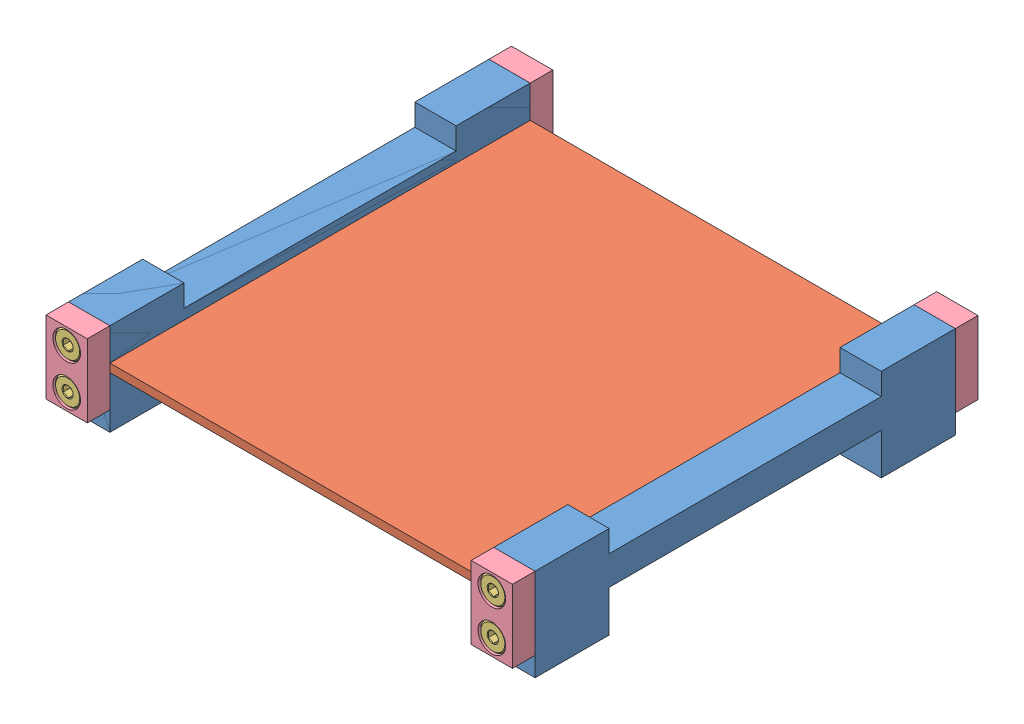
SolidWorks assembly Modified_Stack_Shelves_Assembly, configuration Default. Lengths in mm.
Overall size (96 19 95.8).
16 component instances, 4 part files, 18 mates.
Components (placement in the parent):
- Modified_PCB_Shelf-1: Modified_PCB_Shelf [Default] at origin size (8.5 19 86.5)
- FAKE_PCB-1: FAKE_PCB [Default] at (2.5 6.65 0) size (91 1.7 86.5)
- Modified_PCB_Shelf-2: Modified_PCB_Shelf [Default] at origin size (8.5 19 86.5)
- Modified_PCB_Shelf-4: Modified_PCB_Shelf [Default] at (96 0 -86.5) x (-1 0 0) z (0 0 -1) size (8.5 19 86.5)
- M3_LP_6MM_90666A103_TYPE 316 SS LOW PROFILE SOCKET HEAD CAP SCREW-3: M3_LP_6MM_90666A103_TYPE 316 SS LOW PROFILE SOCKET HEAD CAP SCREW [90666A103] at (4.25 11.675 -3.55) x (1 0 0) z (0 0 -1) size (5.5 5.5 8.16)
- M3_LP_6MM_90666A103_TYPE 316 SS LOW PROFILE SOCKET HEAD CAP SCREW-4: M3_LP_6MM_90666A103_TYPE 316 SS LOW PROFILE SOCKET HEAD CAP SCREW [90666A103] at (4.25 3.325 -3.55) x (1 0 0) z (0 0 -1) size (5.5 5.5 8.16)
- Modified_PCB_Shelf_End-7: Modified_PCB_Shelf_End [Default] at (4.25 7.5 0) size (8.5 15 4.65)
- Modified_PCB_Shelf_End-9: Modified_PCB_Shelf_End [Default] at (91.75 7.5 0) size (8.5 15 4.65)
- M3_LP_6MM_90666A103_TYPE 316 SS LOW PROFILE SOCKET HEAD CAP SCREW-9: M3_LP_6MM_90666A103_TYPE 316 SS LOW PROFILE SOCKET HEAD CAP SCREW [90666A103] at (91.75 11.675 -3.55) x (-1 0 0) z (0 0 -1) size (5.5 5.5 8.16)
- M3_LP_6MM_90666A103_TYPE 316 SS LOW PROFILE SOCKET HEAD CAP SCREW-10: M3_LP_6MM_90666A103_TYPE 316 SS LOW PROFILE SOCKET HEAD CAP SCREW [90666A103] at (91.75 3.325 -3.55) x (-1 0 0) z (0 0 -1) size (5.5 5.5 8.16)
- Modified_PCB_Shelf_End-12: Modified_PCB_Shelf_End [Default] at (91.75 7.5 -86.5) x (-1 0 0) z (0 0 -1) size (8.5 15 4.65)
- Modified_PCB_Shelf_End-13: Modified_PCB_Shelf_End [Default] at (4.25 7.5 -86.5) x (-1 0 0) z (0 0 -1) size (8.5 15 4.65)
- M3_LP_6MM_90666A103_TYPE 316 SS LOW PROFILE SOCKET HEAD CAP SCREW-15: M3_LP_6MM_90666A103_TYPE 316 SS LOW PROFILE SOCKET HEAD CAP SCREW [90666A103] at (4.25 11.675 -82.95) size (5.5 5.5 8.16)
- M3_LP_6MM_90666A103_TYPE 316 SS LOW PROFILE SOCKET HEAD CAP SCREW-16: M3_LP_6MM_90666A103_TYPE 316 SS LOW PROFILE SOCKET HEAD CAP SCREW [90666A103] at (4.25 3.325 -82.95) size (5.5 5.5 8.16)
- M3_LP_6MM_90666A103_TYPE 316 SS LOW PROFILE SOCKET HEAD CAP SCREW-17: M3_LP_6MM_90666A103_TYPE 316 SS LOW PROFILE SOCKET HEAD CAP SCREW [90666A103] at (91.75 11.675 -82.95) x (-1 0 0) z (0 0 1) size (5.5 5.5 8.16)
- M3_LP_6MM_90666A103_TYPE 316 SS LOW PROFILE SOCKET HEAD CAP SCREW-18: M3_LP_6MM_90666A103_TYPE 316 SS LOW PROFILE SOCKET HEAD CAP SCREW [90666A103] at (91.75 3.325 -82.95) x (-1 0 0) z (0 0 1) size (5.5 5.5 8.16)
Mates (geometry in assembly coordinates):
- Coincident1: coincident aligned: line of Modified_PCB_Shelf-1 through (2.5 8.35 -86.5) axis (0 0 1); line of FAKE_PCB-1 through (2.5 8.35 -86.5) axis (0 0 1)
- Coincident2: coincident anti-aligned: line of Modified_PCB_Shelf-1 through (1.7 2.5 6.65) axis (0 0 1); line of FAKE_PCB-1 through (1.7 2.5 8.35) axis (0 0 -1)
- Coincident5: coincident aligned: line of FAKE_PCB-1 through (93.5 8.35 0) axis (0 0 -1); line of Modified_PCB_Shelf-4 through (93.5 8.35 0) axis (0 0 -1)
- Coincident6: coincident anti-aligned: line of FAKE_PCB-1 through (1.7 93.5 8.35) axis (0 0 -1); line of Modified_PCB_Shelf-4 through (93.5 6.65 0) axis (0 1 0)
- Coincident15: coincident anti-aligned: plane of Modified_PCB_Shelf-1 through (8.5 15 0) normal (0 0 1); plane of Modified_PCB_Shelf_End-7 through (4.25 7.5 0) normal (0 0 -1)
- Coincident16: coincident aligned: line of Modified_PCB_Shelf-2 through (8.5 8.5 15) axis (0 -1 0); line of Modified_PCB_Shelf_End-7 through (8.5 8.5 15) axis (0 -1 0)
- Coincident17: coincident aligned: line of Modified_PCB_Shelf-1 through (0 15 0) axis (0 -1 0); line of Modified_PCB_Shelf_End-7 through (15 0 15) axis (0 0 -1)
- Coincident18: coincident anti-aligned: plane of M3_LP_6MM_90666A103_TYPE 316 SS LOW PROFILE SOCKET HEAD CAP SCREW-3 through (4.25 11.675 2.45) normal (0 0 -1); plane of Modified_PCB_Shelf_End-7 through (4.25 11.675 2.45) normal (0 0 1)
- Concentric3: concentric anti-aligned: circle of M3_LP_6MM_90666A103_TYPE 316 SS LOW PROFILE SOCKET HEAD CAP SCREW-3; circle of Modified_PCB_Shelf_End-7
- Coincident19: coincident anti-aligned: plane of Modified_PCB_Shelf-4 through (87.5 0 0) normal (0 0 1); plane of Modified_PCB_Shelf_End-9 through (91.75 7.5 0) normal (0 0 -1)
- Coincident20: coincident aligned: line of Modified_PCB_Shelf-4 through (96 -4 0) axis (0 1 0); line of Modified_PCB_Shelf_End-9 through (15 96 0) axis (0 0 1)
- Coincident21: coincident anti-aligned: line of Modified_PCB_Shelf-4 through (87.5 15 0) axis (1 0 0); line of Modified_PCB_Shelf_End-9 through (8.5 96 15) axis (0 -1 0)
- Coincident22: coincident anti-aligned: plane of Modified_PCB_Shelf-4 through (87.5 15 -86.5) normal (0 0 -1); plane of Modified_PCB_Shelf_End-12 through (91.75 7.5 -86.5) normal (0 0 1)
- Coincident23: coincident aligned: line of Modified_PCB_Shelf-4 through (96 15 -86.5) axis (0 -1 0); line of Modified_PCB_Shelf_End-12 through (96 15 -86.5) axis (0 -1 0)
- Coincident24: coincident aligned: line of Modified_PCB_Shelf-4 through (87.5 15 -86.5) axis (1 0 0); line of Modified_PCB_Shelf_End-12 through (87.5 15 -86.5) axis (1 0 0)
- Coincident25: coincident anti-aligned: plane of Modified_PCB_Shelf-1 through (8.5 0 -86.5) normal (0 0 -1); plane of Modified_PCB_Shelf_End-13 through (4.25 7.5 -86.5) normal (0 0 1)
- Coincident26: coincident aligned: line of Modified_PCB_Shelf-2 through (0 -4 -86.5) axis (0 1 0); line of Modified_PCB_Shelf_End-13 through (0 0 -86.5) axis (0 1 0)
- Coincident27: coincident anti-aligned: line of Modified_PCB_Shelf-2 through (8.5 15 -86.5) axis (-1 0 0); line of Modified_PCB_Shelf_End-13 through (0 15 -86.5) axis (1 0 0)
